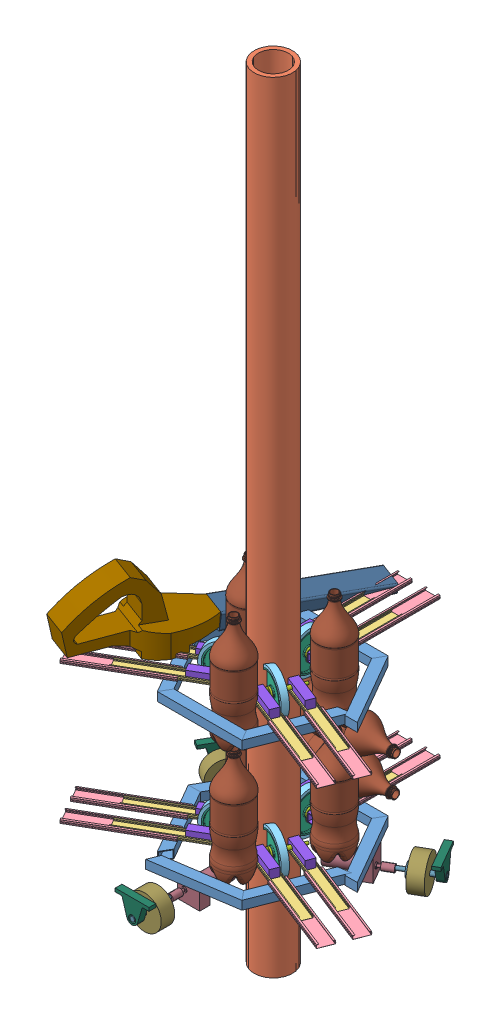
SolidWorks assembly hybrid_new_new, configuration Default. Lengths in mm.
Overall size (1377.45 2307.62 1056.72).
118 component instances, 15 part files, 66 mates.
Components (placement in the parent):
- Part1-1: Part1 [Default] at (62.7195 89.3412 215.5234) size (250 25.4 31.11)
- Part1-2: Part1 [Default] at (-99.5841 89.3412 82.0449) x (0.5 0 0.866025) z (-0.866025 0 0.5) size (250 25.4 31.11)
- Part1-3: Part1 [Default] at (62.7195 -320.6588 215.5234) size (250 25.4 31.11) (hidden)
- Part1-4: Part1 [Default] at (246.6752 89.3412 137.0709) x (0.365335 0 -0.930876) z (0.930876 0 0.365335) size (250 25.4 31.11)
- Part1-5: Part1 [Default] at (293.911 -320.6588 -65.5947) x (-0.5 0 -0.866025) z (0.866025 0 -0.5) size (250 25.4 31.11)
- Part1-6: Part1 [Default] at (-65.1402 -320.6588 -125.2534) x (-0.5 0 0.866025) z (-0.866025 0 -0.5) size (250 25.4 31.11)
- Part1-8: Part1 [Default] at (293.911 89.3412 -65.5947) x (-0.5 0 -0.866025) z (0.866025 0 -0.5) size (250 25.4 31.11)
- Part1-9: Part1 [Default] at (131.6074 -320.6588 -199.0732) x (-1 0 0) z (0 0 -1) size (250 25.4 31.11)
- Part1-10: Part1 [Default] at (-65.1402 89.3412 -125.2534) x (-0.5 0 0.866025) z (-0.866025 0 -0.5) size (250 25.4 31.11)
- Part1-11: Part1 [Default] at (131.6074 89.3412 -199.0732) x (-1 0 0) z (0 0 -1) size (250 25.4 31.11)
- Part1-12: Part1 [Default] at (-99.5841 -320.6588 82.0449) x (0.5 0 0.866025) z (-0.866025 0 0.5) size (250 25.4 31.11)
- pole-1: pole [Default] at (101.0348 -621.7615 10.4602) x (-0.182018 0 -0.983295) z (0.983295 0 -0.182018) size (114 2307.62 114)
- wheel_sys-1: wheel_sys [Default] at (-216.3042 -39.4819 -61.3313) x (0 0 -1) z (1 0 0) size (427.17 170.74 131.58)
  - slider-1: slider [Default] at (295.7545 161.9821 248.2331) size (359 10.5 44.88)
    - inner slider-1: inner slider [Default] at (-151.895 -7.559 16.8408) size (254 10.3 34.88)
    - outer slider-1: outer slider [Default] at (-46.895 -7.759 16.5388) size (254 10.08 44.88)
  - wheelwithaxle-1: wheelwithaxle [Default] at (804.7391 46.5563 384.5567) x (0.829197 -0.558957 0) z (-0.558957 -0.829197 0) size (123 127 123)
    - rim-1: rim [Default] at (-711.4248 -76.2879 334.1654) size (123 19 123)
    - centre-1: centre [Default] at (-711.4248 -76.2879 334.1654) size (107 19 107)
    - wheel axle-1: wheel axle [Default] at (-713.6031 -81.7741 334.1654) size (28 127 28)
  - slider-2: slider [Default] at (295.7545 161.9821 330.8673) size (359 10.5 44.88)
    - inner slider-1: inner slider [Default] at (-151.895 -7.559 16.8408) size (254 10.3 34.88)
    - outer slider-1: outer slider [Default] at (-46.895 -7.759 16.5388) size (254 10.08 44.88)
  - support-1: support [Default] at (-18.9561 167.1231 347.1618) x (0 -1 0) z (0 0 1) size (25 90.2 25)
  - support-2: support [Default] at (-18.9561 167.1231 265.119) x (0 -1 0) z (0 0 1) size (25 90.2 25)
- wheel_sys-2: wheel_sys [Default] at (198.0796 -39.4819 322.1299) x (-0.866025 0 0.5) z (-0.5 0 -0.866025) size (427.17 170.74 131.58)
  - slider-1: slider [Default] at (295.7545 161.9821 248.2331) size (359 10.5 44.88)
    - inner slider-1: inner slider [Default] at (-151.895 -7.559 16.8408) size (254 10.3 34.88)
    - outer slider-1: outer slider [Default] at (-46.895 -7.759 16.5388) size (254 10.08 44.88)
  - wheelwithaxle-1: wheelwithaxle [Default] at (804.7391 46.5563 384.5567) x (0.829197 -0.558957 0) z (-0.558957 -0.829197 0) size (123 127 123)
    - rim-1: rim [Default] at (-711.4248 -76.2879 334.1654) size (123 19 123)
    - centre-1: centre [Default] at (-711.4248 -76.2879 334.1654) size (107 19 107)
    - wheel axle-1: wheel axle [Default] at (-713.6031 -81.7741 334.1654) size (28 127 28)
  - slider-2: slider [Default] at (295.7545 161.9821 330.8673) size (359 10.5 44.88)
    - inner slider-1: inner slider [Default] at (-151.895 -7.559 16.8408) size (254 10.3 34.88)
    - outer slider-1: outer slider [Default] at (-46.895 -7.759 16.5388) size (254 10.08 44.88)
  - support-1: support [Default] at (-18.9561 167.1231 347.1618) x (0 -1 0) z (0 0 1) size (25 90.2 25)
  - support-2: support [Default] at (-18.9561 167.1231 265.119) x (0 -1 0) z (0 0 1) size (25 90.2 25)
- wheel_sys-3: wheel_sys [Default] at (246.8767 -39.4819 -240.4713) x (0.930876 0 0.365335) z (-0.365335 0 0.930876) size (427.17 170.74 131.58)
  - slider-1: slider [Default] at (295.7545 161.9821 248.2331) size (359 10.5 44.88)
    - inner slider-1: inner slider [Default] at (-151.895 -7.559 16.8408) size (254 10.3 34.88)
    - outer slider-1: outer slider [Default] at (-46.895 -7.759 16.5388) size (254 10.08 44.88)
  - wheelwithaxle-1: wheelwithaxle [Default] at (804.7391 46.5563 384.5567) x (0.829197 -0.558957 0) z (-0.558957 -0.829197 0) size (123 127 123)
    - rim-1: rim [Default] at (-711.4248 -76.2879 334.1654) size (123 19 123)
    - centre-1: centre [Default] at (-711.4248 -76.2879 334.1654) size (107 19 107)
    - wheel axle-1: wheel axle [Default] at (-713.6031 -81.7741 334.1654) size (28 127 28)
  - slider-2: slider [Default] at (295.7545 161.9821 330.8673) size (359 10.5 44.88)
    - inner slider-1: inner slider [Default] at (-151.895 -7.559 16.8408) size (254 10.3 34.88)
    - outer slider-1: outer slider [Default] at (-46.895 -7.759 16.5388) size (254 10.08 44.88)
  - support-1: support [Default] at (-18.9561 167.1231 347.1618) x (0 -1 0) z (0 0 1) size (25 90.2 25)
  - support-2: support [Default] at (-18.9561 167.1231 265.119) x (0 -1 0) z (0 0 1) size (25 90.2 25)
- blower_assemb-1: blower_assemb [Default] at (-520.3544 35.9897 11.0958) x (0.347965 0 -0.937507) z (0.937507 0 0.347965) size (835.33 242.61 170.56)
  - blower-1: blower [Default] at (211.986 78.7515 400.2885) size (835.33 223.79 170.56)
  - nozzle-1: nozzle [Default] at (178.078 64.9806 320.83) x (0.993475 -0.11405 0) z (0 0 1) size (410 47.38 80)
- 2l_cola_bottle-1: 2l_cola_bottle [Standard] at (-175.2913 7.0912 -42.2725) size (104.49 326.54 105)
- 2l_cola_bottle-2: 2l_cola_bottle [Standard] at (-41.6978 7.0912 139.5723) size (104.49 326.54 105)
- 2l_cola_bottle-3: 2l_cola_bottle [Standard] at (49.0019 7.0912 -67.887) size (104.49 326.54 105)
- 2l_cola_bottle-6: 2l_cola_bottle [Standard] at (-76.7175 -251.3106 -270.9861) x (0 0.885599 0.464451) z (0 0.464451 -0.885599) size (104.49 326.54 105)
- 2l_cola_bottle-7: 2l_cola_bottle [Standard] at (49.0019 -335.5167 -67.887) size (104.49 326.54 105)
- 2l_cola_bottle-8: 2l_cola_bottle [Standard] at (-175.2543 -335.5167 -45.6556) x (0.999761 0 0.021868) z (-0.021868 0 0.999761) size (104.49 326.54 105)
- 2l_cola_bottle-9: 2l_cola_bottle [Standard] at (-40.9049 -335.5167 123.9293) x (0.994874 0 0.101118) z (-0.101118 0 0.994874) size (104.49 326.54 105)
- 2l_cola_bottle-10: 2l_cola_bottle [Standard] at (-76.7175 -298.0239 -64.0606) x (0 0.514567 -0.85745) z (0 -0.85745 -0.514567) size (104.49 326.54 105)
- wheel_sys-7: wheel_sys [Default] at (-216.3042 -449.4819 -61.3313) x (0 0 -1) z (1 0 0) size (427.17 170.74 131.58)
  - slider-1: slider [Default] at (295.7545 161.9821 248.2331) size (359 10.5 44.88)
    - inner slider-1: inner slider [Default] at (-151.895 -7.559 16.8408) size (254 10.3 34.88)
    - outer slider-1: outer slider [Default] at (-46.895 -7.759 16.5388) size (254 10.08 44.88)
  - wheelwithaxle-1: wheelwithaxle [Default] at (804.7391 46.5563 384.5567) x (0.829197 -0.558957 0) z (-0.558957 -0.829197 0) size (123 127 123)
    - rim-1: rim [Default] at (-711.4248 -76.2879 334.1654) size (123 19 123)
    - centre-1: centre [Default] at (-711.4248 -76.2879 334.1654) size (107 19 107)
    - wheel axle-1: wheel axle [Default] at (-713.6031 -81.7741 334.1654) size (28 127 28)
  - slider-2: slider [Default] at (295.7545 161.9821 330.8673) size (359 10.5 44.88)
    - inner slider-1: inner slider [Default] at (-151.895 -7.559 16.8408) size (254 10.3 34.88)
    - outer slider-1: outer slider [Default] at (-46.895 -7.759 16.5388) size (254 10.08 44.88)
  - support-1: support [Default] at (-18.9561 167.1231 347.1618) x (0 -1 0) z (0 0 1) size (25 90.2 25)
  - support-2: support [Default] at (-18.9561 167.1231 265.119) x (0 -1 0) z (0 0 1) size (25 90.2 25)
- wheel_sys-8: wheel_sys [Default] at (198.0796 -449.4819 322.1299) x (-0.866025 0 0.5) z (-0.5 0 -0.866025) size (427.17 170.74 131.58)
  - slider-1: slider [Default] at (295.7545 161.9821 248.2331) size (359 10.5 44.88)
    - inner slider-1: inner slider [Default] at (-151.895 -7.559 16.8408) size (254 10.3 34.88)
    - outer slider-1: outer slider [Default] at (-46.895 -7.759 16.5388) size (254 10.08 44.88)
  - wheelwithaxle-1: wheelwithaxle [Default] at (804.7391 46.5563 384.5567) x (0.829197 -0.558957 0) z (-0.558957 -0.829197 0) size (123 127 123)
    - rim-1: rim [Default] at (-711.4248 -76.2879 334.1654) size (123 19 123)
    - centre-1: centre [Default] at (-711.4248 -76.2879 334.1654) size (107 19 107)
    - wheel axle-1: wheel axle [Default] at (-713.6031 -81.7741 334.1654) size (28 127 28)
  - slider-2: slider [Default] at (295.7545 161.9821 330.8673) size (359 10.5 44.88)
    - inner slider-1: inner slider [Default] at (-151.895 -7.559 16.8408) size (254 10.3 34.88)
    - outer slider-1: outer slider [Default] at (-46.895 -7.759 16.5388) size (254 10.08 44.88)
  - support-1: support [Default] at (-18.9561 167.1231 347.1618) x (0 -1 0) z (0 0 1) size (25 90.2 25)
  - support-2: support [Default] at (-18.9561 167.1231 265.119) x (0 -1 0) z (0 0 1) size (25 90.2 25)
- wheel_sys-9: wheel_sys [Default] at (246.8767 -449.4819 -240.4713) x (0.930876 0 0.365335) z (-0.365335 0 0.930876) size (427.17 170.74 131.58)
  - slider-1: slider [Default] at (295.7545 161.9821 248.2331) size (359 10.5 44.88)
    - inner slider-1: inner slider [Default] at (-151.895 -7.559 16.8408) size (254 10.3 34.88)
    - outer slider-1: outer slider [Default] at (-46.895 -7.759 16.5388) size (254 10.08 44.88)
  - wheelwithaxle-1: wheelwithaxle [Default] at (804.7391 46.5563 384.5567) x (0.829197 -0.558957 0) z (-0.558957 -0.829197 0) size (123 127 123)
    - rim-1: rim [Default] at (-711.4248 -76.2879 334.1654) size (123 19 123)
    - centre-1: centre [Default] at (-711.4248 -76.2879 334.1654) size (107 19 107)
    - wheel axle-1: wheel axle [Default] at (-713.6031 -81.7741 334.1654) size (28 127 28)
  - slider-2: slider [Default] at (295.7545 161.9821 330.8673) size (359 10.5 44.88)
    - inner slider-1: inner slider [Default] at (-151.895 -7.559 16.8408) size (254 10.3 34.88)
    - outer slider-1: outer slider [Default] at (-46.895 -7.759 16.5388) size (254 10.08 44.88)
  - support-1: support [Default] at (-18.9561 167.1231 347.1618) x (0 -1 0) z (0 0 1) size (25 90.2 25)
  - support-2: support [Default] at (-18.9561 167.1231 265.119) x (0 -1 0) z (0 0 1) size (25 90.2 25)
- Part1-13: Part1 [Default] at (246.6752 -320.6588 137.0709) x (0.365335 0 -0.930876) z (0.930876 0 0.365335) size (250 25.4 31.11)
- Wheel_sys_lower-1: Wheel_sys_lower [Default] at (-267.2535 -516.7508 -98.9365) x (-0.584128 -0.028115 0.811174) z (-0.233785 0.962874 -0.134976) size (141.79 280.46 162.59)
  - omni-1: omni [Default] at (-77.0455 69.9199 150.3063) x (0.545954 -0.173862 -0.819577) z (0.831792 0.229571 0.50539) size (100 40 100)
  - motor-1: motor [Default] at (-76.5038 184.1966 116.3052) x (0.994562 0.104149 0) z (-0.028115 0.268484 0.962874) size (65 158 65)
  - shaft-1: shaft [Default] at (-87.3634 168.4493 120.2645) x (-0.994562 -0.104149 0) z (-0.028115 0.268484 0.962874) size (38.13 139.7 38.13)
  - support_lower_wheel-1: support_lower_wheel [Default] at (-76.2241 54.2728 211.6456) x (0.994562 0.104149 0) z (-0.100283 0.957637 -0.269952) size (100 70 20)
- Wheel_sys_lower-2: Wheel_sys_lower [Default] at (370.3499 -516.7508 -256.9523) x (-0.410434 -0.028115 -0.911457) z (0.233785 0.962874 -0.134976) size (141.79 280.46 162.59)
  - omni-1: omni [Default] at (-77.0455 69.9199 150.3063) x (0.545954 -0.173862 -0.819577) z (0.831792 0.229571 0.50539) size (100 40 100)
  - motor-1: motor [Default] at (-76.5038 184.1966 116.3052) x (0.994562 0.104149 0) z (-0.028115 0.268484 0.962874) size (65 158 65)
  - shaft-1: shaft [Default] at (-87.3634 168.4493 120.2645) x (-0.994562 -0.104149 0) z (-0.028115 0.268484 0.962874) size (38.13 139.7 38.13)
  - support_lower_wheel-1: support_lower_wheel [Default] at (-76.2241 54.2728 211.6456) x (0.994562 0.104149 0) z (-0.100283 0.957637 -0.269952) size (100 70 20)
- Wheel_sys_lower-3: Wheel_sys_lower [Default] at (121.5672 -516.7508 377.4002) x (0.994562 -0.028115 0.100283) z (0 0.962874 0.269952) size (141.79 280.46 162.59)
  - omni-1: omni [Default] at (-77.0455 69.9199 150.3063) x (0.545954 -0.173862 -0.819577) z (0.831792 0.229571 0.50539) size (100 40 100)
  - motor-1: motor [Default] at (-76.5038 184.1966 116.3052) x (0.994562 0.104149 0) z (-0.028115 0.268484 0.962874) size (65 158 65)
  - shaft-1: shaft [Default] at (-87.3634 168.4493 120.2645) x (-0.994562 -0.104149 0) z (-0.028115 0.268484 0.962874) size (38.13 139.7 38.13)
  - support_lower_wheel-1: support_lower_wheel [Default] at (-76.2241 54.2728 211.6456) x (0.994562 0.104149 0) z (-0.100283 0.957637 -0.269952) size (100 70 20)
- Part1-14: Part1 [Default] at (63.128 -320.6588 239.3911) x (0.98883 0 -0.149048) z (0.149048 0 0.98883) size (250 25.4 31.11)
Mates (geometry in assembly coordinates):
- Coincident1: coincident aligned: plane of Part1-2 through (-99.5841 114.7412 82.0449) normal (0 1 0); plane of Part1-4 through (246.6752 114.7412 137.0709) normal (0 1 0)
- Coincident2: coincident aligned: plane of Part1-8 through (293.911 114.7412 -65.5947) normal (0 1 0); plane of Part1-11 through (131.6074 114.7412 -199.0732) normal (0 1 0)
- Coincident3: coincident aligned: plane of Part1-1 through (62.7195 114.7412 215.5234) normal (0 1 0); plane of Part1-10 through (-65.1402 114.7412 -125.2534) normal (0 1 0)
- Coincident4: coincident aligned: plane of Part1-1 through (62.7195 114.7412 215.5234) normal (0 1 0); plane of Part1-4 through (246.6752 114.7412 137.0709) normal (0 1 0)
- Coincident5: coincident aligned: plane of Part1-4 through (246.6752 114.7412 137.0709) normal (0 1 0); plane of Part1-8 through (293.911 114.7412 -65.5947) normal (0 1 0)
- Coincident6: coincident anti-aligned: plane of Part1-8 through (222.1634 114.7412 -208.2813) normal (-0.866025 0 -0.5); plane of Part1-11 through (222.1634 114.7412 -208.2813) normal (0.866025 0 0.5)
- Coincident7: coincident aligned: line of Part1-8 through (222.1634 114.7412 -208.2813) axis (0 -1 0); line of Part1-11 through (222.1634 114.7412 -208.2813) axis (0 -1 0)
- Coincident8: coincident anti-aligned: plane of Part1-10 through (-27.8366 114.7412 -208.2813) normal (0.866025 0 -0.5); plane of Part1-11 through (-27.8366 114.7412 -208.2813) normal (-0.866025 0 0.5)
- Coincident9: coincident aligned: line of Part1-10 through (-27.8366 114.7412 -208.2813) axis (0 -1 0); line of Part1-11 through (-27.8366 114.7412 -208.2813) axis (0 -1 0)
- Coincident10: coincident anti-aligned: plane of Part1-2 through (-152.8366 114.7412 8.2251) normal (0 0 -1); plane of Part1-10 through (-152.8366 114.7412 8.2251) normal (0 0 1)
- Coincident11: coincident aligned: line of Part1-2 through (-152.8366 114.7412 8.2251) axis (0 -1 0); line of Part1-10 through (-152.8366 114.7412 8.2251) axis (0 -1 0)
- Coincident12: coincident anti-aligned: plane of Part1-1 through (-27.8366 114.7412 224.7314) normal (-0.866025 0 -0.5); plane of Part1-2 through (-27.8366 114.7412 224.7314) normal (0.866025 0 0.5)
- Coincident13: coincident aligned: line of Part1-1 through (-27.8366 114.7412 224.7314) axis (0 -1 0); line of Part1-2 through (-27.8366 114.7412 224.7314) axis (0 -1 0)
- Coincident14: coincident aligned: line of Part1-1 through (222.1634 114.7412 224.7314) axis (0 -1 0); line of Part1-4 through (222.1634 114.7412 224.7314) axis (0 -1 0)
- Coincident16: coincident aligned: plane of Part1-6 through (-65.1402 -295.2588 -125.2534) normal (0 1 0); plane of Part1-12 through (-99.5841 -295.2588 82.0449) normal (0 1 0)
- Coincident17: coincident aligned: plane of Part1-5 through (293.911 -295.2588 -65.5947) normal (0 1 0); plane of Part1-9 through (131.6074 -295.2588 -199.0732) normal (0 1 0)
- Coincident18: coincident aligned: plane of Part1-5 through (293.911 -295.2588 -65.5947) normal (0 1 0); plane of Part1-6 through (-65.1402 -295.2588 -125.2534) normal (0 1 0)
- Coincident19: coincident aligned: plane of Part1-3 through (62.7195 -295.2588 215.5234) normal (0 1 0); plane of Part1-6 through (-65.1402 -295.2588 -125.2534) normal (0 1 0)
- Coincident21: coincident anti-aligned: plane of Part1-5 through (222.1634 -295.2588 -208.2813) normal (-0.866025 0 -0.5); plane of Part1-9 through (222.1634 -295.2588 -208.2813) normal (0.866025 0 0.5)
- Coincident22: coincident aligned: line of Part1-5 through (222.1634 -295.2588 -208.2813) axis (0 -1 0); line of Part1-9 through (222.1634 -295.2588 -208.2813) axis (0 -1 0)
- Coincident23: coincident anti-aligned: plane of Part1-6 through (-27.8366 -295.2588 -208.2813) normal (0.866025 0 -0.5); plane of Part1-9 through (-27.8366 -295.2588 -208.2813) normal (-0.866025 0 0.5)
- Coincident24: coincident aligned: line of Part1-6 through (-27.8366 -295.2588 -208.2813) axis (0 -1 0); line of Part1-9 through (-27.8366 -295.2588 -208.2813) axis (0 -1 0)
- Coincident25: coincident anti-aligned: plane of Part1-6 through (-152.8366 -295.2588 8.2251) normal (0 0 1); plane of Part1-12 through (-152.8366 -295.2588 8.2251) normal (0 0 -1)
- Coincident26: coincident aligned: line of Part1-6 through (-152.8366 -295.2588 8.2251) axis (0 -1 0); line of Part1-12 through (-152.8366 -295.2588 8.2251) axis (0 -1 0)
- Coincident27: coincident anti-aligned: plane of Part1-3 through (-27.8366 -295.2588 224.7314) normal (-0.866025 0 -0.5); plane of Part1-12 through (-27.8366 -295.2588 224.7314) normal (0.866025 0 0.5)
- Coincident28: coincident aligned: line of Part1-3 through (-27.8366 -295.2588 224.7314) axis (0 -1 0); line of Part1-12 through (-27.8366 -295.2588 224.7314) axis (0 -1 0)
- Distance3: distance = 410 mm aligned: plane of Part1-1 through (62.7195 114.7412 215.5234) normal (0 1 0); plane of Part1-3 through (62.7195 -295.2588 215.5234) normal (0 1 0)
- Coincident36: coincident aligned: plane of Part1-6 through (-9.8761 -295.2588 -177.1727) normal (0.866025 0 0.5); plane of Part1-10 through (-9.8761 114.7412 -177.1727) normal (0.866025 0 0.5)
- Coincident37: coincident aligned: plane of Part1-9 through (204.2029 -295.2588 -177.1727) normal (0 0 1); plane of Part1-11 through (204.2029 114.7412 -177.1727) normal (0 0 1)
- Perpendicular3: perpendicular: axis of pole-1 through (101.0348 1685.8585 10.4602) axis (0 -1 0); line of assembly
- Distance22: distance = 1685.8585 mm aligned: plane of pole-1 through (101.0348 1685.8585 10.4602) normal (0 1 0); plane of assembly through (0 0 0) normal (0 1 0)
- Coincident82: coincident: axis of pole-1 through (101.0348 1685.8585 10.4602) axis (0 -1 0); plane of assembly
- Coincident87: coincident anti-aligned: plane of Part1-10 through (-65.1402 114.7412 -125.2534) normal (0 1 0); plane of wheel_sys-1/slider-2/outer slider-1 through (131.1019 114.7412 -310.1909) normal (0 -1 0)
- Coincident88: coincident anti-aligned: plane of Part1-11 through (131.6074 114.7412 -199.0732) normal (0 1 0); plane of wheel_sys-2/slider-2/outer slider-1 through (-191.1421 114.7412 145.6972) normal (0 -1 0)
- Coincident89: coincident aligned: plane of Part1-11 through (204.2029 114.7412 -177.1727) normal (0 0 1); plane of wheel_sys-1/slider-1/outer slider-1 through (26.9676 114.9412 -177.1727) normal (0 0 1)
- Coincident90: coincident aligned: plane of Part1-2 through (-116.9155 114.7412 8.2251) normal (0.866025 0 -0.5); plane of wheel_sys-2/slider-1/outer slider-1 through (-23.8779 114.9412 169.371) normal (0.866025 0 -0.5)
- Distance25: distance = 69.765 mm: point of Part1-8; line of wheel_sys-1/slider-2/outer slider-1 through (152.3987 114.9412 -431.1727) axis (0 0 1)
- Distance26: distance = 83.0998 mm: point of Part1-10; line of wheel_sys-2/slider-2/inner slider-1 through (6.5866 114.9412 12.1372) axis (-0.866025 0 0.5)
- Coincident94: coincident aligned: plane of Part1-4 through (199.7669 114.7412 196.6474) normal (-0.930876 0 -0.365335); plane of wheel_sys-3/slider-2/outer slider-1 through (235.6457 114.9412 105.2278) normal (-0.930876 0 -0.365335)
- Coincident95: coincident anti-aligned: plane of Part1-4 through (246.6752 114.7412 137.0709) normal (0 1 0); plane of wheel_sys-3/slider-2/outer slider-1 through (351.6145 114.7412 173.8379) normal (0 -1 0)
- Distance27: distance = 77.8669 mm: point of Part1-4; line of wheel_sys-3/slider-2/inner slider-1 through (123.9107 114.9412 102.522) axis (0.930876 0 0.365335)
- Coincident96: coincident anti-aligned: plane of Part1-1 through (62.7195 114.7412 215.5234) normal (0 1 0); plane of blower_assemb-1/blower-1 through (-71.3172 114.7412 -48.3561) normal (0 -1 0)
- Coincident98: coincident aligned: plane of 2l_cola_bottle-8 through (-32.889 -3.2315 -42.5415) normal (0 1 0); plane of 2l_cola_bottle-9 through (100.7646 -3.2315 138.3285) normal (0 1 0)
- Coincident99: coincident aligned: plane of 2l_cola_bottle-7 through (191.4012 -3.2315 -67.887) normal (0 1 0); plane of 2l_cola_bottle-8 through (-32.889 -3.2315 -42.5415) normal (0 1 0)
- Coincident100: coincident: plane of 2l_cola_bottle-2 through (100.7015 339.3764 139.5723) normal (0 1 0); circle of 2l_cola_bottle-1
- Coincident101: coincident aligned: plane of 2l_cola_bottle-2 through (100.7015 339.3764 139.5723) normal (0 1 0); plane of 2l_cola_bottle-3 through (191.4012 339.3764 -67.887) normal (0 1 0)
- Coincident102: coincident aligned: axis of 2l_cola_bottle-2 through (113.0015 241.9911 139.5723) axis (0 1 0); axis of 2l_cola_bottle-9 through (113.0015 -144.9684 139.5723) axis (0 1 0)
- Coincident103: coincident aligned: axis of 2l_cola_bottle-1 through (-20.5919 117.3724 -42.2725) axis (0 1 0); axis of 2l_cola_bottle-8 through (-20.5919 -144.9684 -42.2725) axis (0 1 0)
- Coincident104: coincident aligned: axis of 2l_cola_bottle-3 through (203.7012 117.3724 -67.887) axis (0 1 0); axis of 2l_cola_bottle-7 through (203.7012 -144.9684 -67.887) axis (0 1 0)
- Coincident110: coincident aligned: plane of 2l_cola_bottle-6 through (255.5676 -125.2019 -204.8486) normal (1 0 0); plane of 2l_cola_bottle-10 through (255.5676 -224.7499 -186.1609) normal (1 0 0)
- Distance31: distance = 104.14 mm: axis of 2l_cola_bottle-6 through (113.8308 -114.3091 -199.1359) axis (1 0 0); axis of 2l_cola_bottle-10 through (-61.8598 -218.4207 -196.7075) axis (1 0 0)
- Coincident111: coincident anti-aligned: plane of Part1-3 through (62.7195 -320.6588 215.5234) normal (0 -1 0); plane of Wheel_sys_lower-3/motor-1 through (32.1634 -320.6588 194.7314) normal (0 1 0)
- Coincident112: coincident aligned: plane of Wheel_sys_lower-2/motor-1 through (256.856 -320.6588 -88.192) normal (0 1 0); plane of Wheel_sys_lower-3/motor-1 through (32.1634 -320.6588 194.7314) normal (0 1 0)
- Coincident113: coincident aligned: plane of Wheel_sys_lower-1/motor-1 through (-64.3558 -320.6588 -85.0281) normal (0 1 0); plane of Wheel_sys_lower-2/motor-1 through (256.856 -320.6588 -88.192) normal (0 1 0)
- Parallel1: parallel anti-aligned: plane of Part1-6 through (-27.8366 -295.2588 -208.2813) normal (-0.866025 0 -0.5); plane of Wheel_sys_lower-1/motor-1 through (-6.9937 -353.1588 -14.3823) normal (0.866025 0 0.5)
- Coincident115: coincident aligned: line of Part1-6 through (-27.8366 -320.6588 -208.2813) axis (-0.5 0 0.866025); line of Wheel_sys_lower-1/motor-1 through (-90.3366 -320.6588 -100.0281) axis (-0.5 0 0.866025)
- Distance32: distance = 125 mm: line of Wheel_sys_lower-1/motor-1 through (-90.3366 -385.6588 -100.0281) axis (0 1 0); line of Part1-6 through (-27.8366 -295.2588 -208.2813) axis (0 -1 0)
- Parallel3: parallel aligned: line of Part1-5 through (347.1634 -295.2588 8.2251) axis (-0.5 0 -0.866025); line of Wheel_sys_lower-2/motor-1 through (282.8367 -320.6588 -103.192) axis (-0.5 0 -0.866025)
- Distance33: distance = 125 mm: line of Wheel_sys_lower-2/motor-1 through (256.856 -385.6588 -88.192) axis (0 1 0); line of Part1-9 through (222.1634 -295.2588 -208.2813) axis (0 -1 0)
- Coincident120: coincident aligned: plane of Part1-5 through (347.1634 -295.2588 8.2251) normal (0.866025 0 -0.5); plane of Wheel_sys_lower-2/motor-1 through (266.5867 -353.1588 -131.3378) normal (0.866025 0 -0.5)
- Coincident121: coincident aligned: plane of Part1-3 through (-27.8366 -295.2588 224.7314) normal (0 0 1); plane of Wheel_sys_lower-3/motor-1 through (64.6634 -353.1588 224.7314) normal (0 0 1)
- Distance34: distance = 125 mm: line of Part1-13 through (222.1634 -295.2588 224.7314) axis (0 -1 0); line of Wheel_sys_lower-3/motor-1 through (97.1634 -320.6588 224.7314) axis (0 -1 0)
- Distance37: distance = 224.6352 mm: plane of 2l_cola_bottle-2 through (100.7015 339.3764 139.5723) normal (0 1 0); plane of Part1-1 through (62.7195 114.7412 215.5234) normal (0 1 0)
- Coincident122: coincident aligned: plane of Part1-13 through (246.6752 -295.2588 137.0709) normal (0 1 0); plane of Part1-14 through (63.128 -295.2588 239.3911) normal (0 1 0)
- Coincident123: coincident anti-aligned: plane of Part1-13 through (222.1634 -295.2588 224.7314) normal (-0.781828 0 0.623495); plane of Part1-14 through (222.1634 -295.2588 224.7314) normal (0.781828 0 -0.623495)
- Coincident124: coincident aligned: line of Part1-13 through (222.1634 -295.2588 224.7314) axis (0 -1 0); line of Part1-14 through (222.1634 -295.2588 224.7314) axis (0 -1 0)
